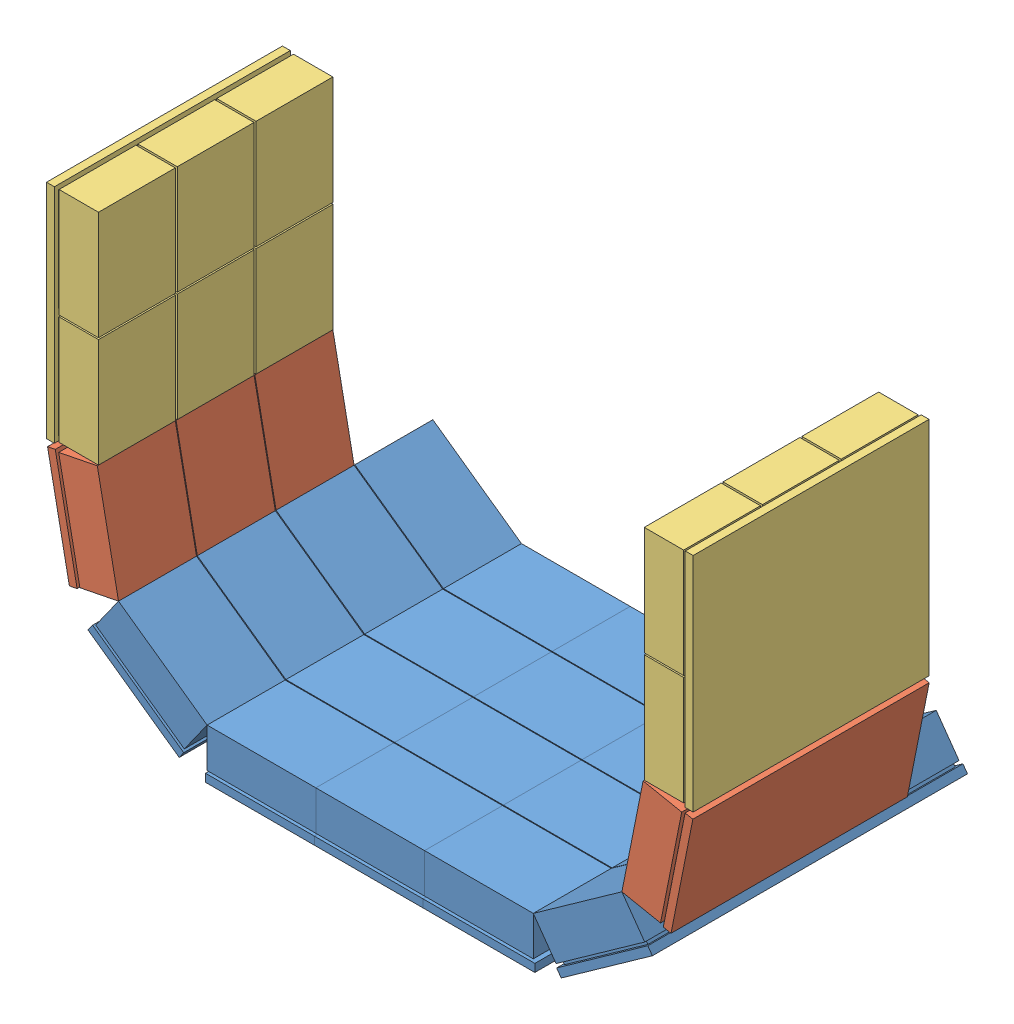
SolidWorks assembly Detector_posterial2, configuration Default. Lengths in mm.
Overall size (410.4 279.65 200.24).
9 component instances, 3 part files, 23 mates.
Components (placement in the parent):
- 1Detector-1: 1Detector [Default] at (83.9721 85.3161 150.6758) size (71 32 200)
- 1Detector-2: 1Detector [Default] at (152.9721 85.3161 150.6758) size (71 32 200)
- 1Detector-3: 1Detector [Default] at (14.9721 85.3161 150.6758) size (71 32 200)
- 1Detector-4: 1Detector [Default] at (-66.1879 111.2254 150.6758) x (0.815027 -0.579423 0) z (0 0 1) size (71 32 200)
- 1Detector-5: 1Detector [Default] at (234.132 111.2254 150.6758) x (0.815027 0.579423 0) z (0 0 1) size (71 32 200)
- 1Detector_3modules-1: 1Detector_3modules [Default] at (-113.8805 184.8905 175.6758) x (0.19509 -0.980785 0) z (0 0 1) size (71 32 150)
- 1Detector_3modules-2: 1Detector_3modules [Default] at (281.8247 184.8905 175.6758) x (0.19509 0.980785 0) z (0 0 1) size (71 32 150)
- top_bottomDetector2-1: top_bottomDetector2 [Default] at (289.1701 259.4705 125.9183) x (0 1 0) z (0 0 1) size (141 32 149.74)
- top_bottomDetector2-2: top_bottomDetector2 [Default] at (-121.226 329.4705 125.9183) x (0 -1 0) z (0 0 1) size (141 32 149.74)
Mates (geometry in assembly coordinates):
- Coincident2: coincident anti-aligned: line of 1Detector-1 through (118.4721 117.3161 250.6758) axis (0 0 -1); line of 1Detector-2 through (118.4721 117.3161 201.1758) axis (0 0 1)
- Coincident19: coincident aligned: line of 1Detector-1 through (49.4721 117.3161 250.6758) axis (1 0 0); line of 1Detector-2 through (118.4721 117.3161 250.6758) axis (1 0 0)
- Coincident4: coincident: point of 1Detector-1; point of 1Detector-2
- Coincident5: coincident anti-aligned: line of 1Detector-1 through (49.4721 117.3161 201.1758) axis (0 0 1); line of 1Detector-3 through (49.4721 117.3161 250.6758) axis (0 0 -1)
- Coincident20: coincident aligned: line of 1Detector-1 through (49.4721 117.3161 250.6758) axis (1 0 0); line of 1Detector-3 through (-19.5279 117.3161 250.6758) axis (1 0 0)
- Coincident7: coincident: point of 1Detector-1; point of 1Detector-3
- Coincident8: coincident anti-aligned: line of 1Detector-2 through (187.4721 117.3161 250.6758) axis (0 0 -1); line of 1Detector-5 through (187.4721 117.3161 201.1758) axis (0 0 1)
- Angle3: planar angle = 2.523572 rad anti-aligned: line of 1Detector-2 through (118.4721 117.3161 250.6758) axis (1 0 0); line of 1Detector-5 through (187.4721 117.3161 250.6758) axis (0.815027 0.579423 0)
- Coincident10: coincident anti-aligned: line of 1Detector-3 through (-19.5279 117.3161 201.1758) axis (0 0 1); line of 1Detector-4 through (-19.5279 117.3161 250.6758) axis (0 0 -1)
- Angle4: planar angle = 2.523572 rad anti-aligned: line of 1Detector-4 through (-75.7648 157.2963 250.6758) axis (0.815027 -0.579423 0); line of 1Detector-3 through (-19.5279 117.3161 250.6758) axis (1 0 0)
- Coincident12: coincident: point of 1Detector-3; point of 1Detector-4
- Coincident13: coincident anti-aligned: line of 1Detector-4 through (-75.7648 157.2963 201.1758) axis (0 0 1); line of 1Detector_3modules-1 through (-75.7648 157.2963 250.6758) axis (0 0 -1)
- Angle5: planar angle = 2.385167 rad anti-aligned: line of 1Detector_3modules-1 through (-89.226 224.9705 250.6758) axis (0.19509 -0.980785 0); line of 1Detector-4 through (-75.7648 157.2963 250.6758) axis (0.815027 -0.579423 0)
- Coincident15: coincident: point of 1Detector-4; point of 1Detector_3modules-1
- Coincident16: coincident anti-aligned: line of 1Detector-5 through (251.8891 142.0435 250.6758) axis (0 0 -1); line of 1Detector_3modules-2 through (251.8891 142.0435 201.1758) axis (0 0 1)
- Angle6: planar angle = 2.385167 rad anti-aligned: line of 1Detector-5 through (187.4721 117.3161 250.6758) axis (0.815027 0.579423 0); line of 1Detector_3modules-2 through (243.7089 157.2963 250.6758) axis (0.19509 0.980785 0)
- Coincident18: coincident: point of 1Detector-5; point of 1Detector_3modules-2
- Coincident21: coincident: line of 1Detector_3modules-1 through (-89.226 224.9705 101.1758) axis (0 0 1); line of top_bottomDetector2-2 through (-89.226 224.9705 149.9307) axis (0 0 -1)
- Coincident22: coincident: point of 1Detector_3modules-1; point of top_bottomDetector2-2
- Angle7: planar angle = 2.945243 rad anti-aligned: line of top_bottomDetector2-2 through (-89.226 224.9705 101.1758) axis (0 1 0); line of 1Detector_3modules-1 through (-75.7648 157.2963 101.1758) axis (-0.19509 0.980785 0)
- Coincident24: coincident anti-aligned: line of 1Detector_3modules-2 through (281.7682 204.2387 150.6758) axis (0 0 -1); line of top_bottomDetector2-1 through (281.7682 204.2387 101.1758) axis (0 0 1)
- Coincident25: coincident: point of 1Detector_3modules-2; point of top_bottomDetector2-1
- Angle8: planar angle = 0.19635 rad aligned: line of top_bottomDetector2-1 through (257.1701 293.9705 101.1758) axis (0 -1 0); line of 1Detector_3modules-2 through (257.1701 224.9705 101.1758) axis (-0.19509 -0.980785 0)
